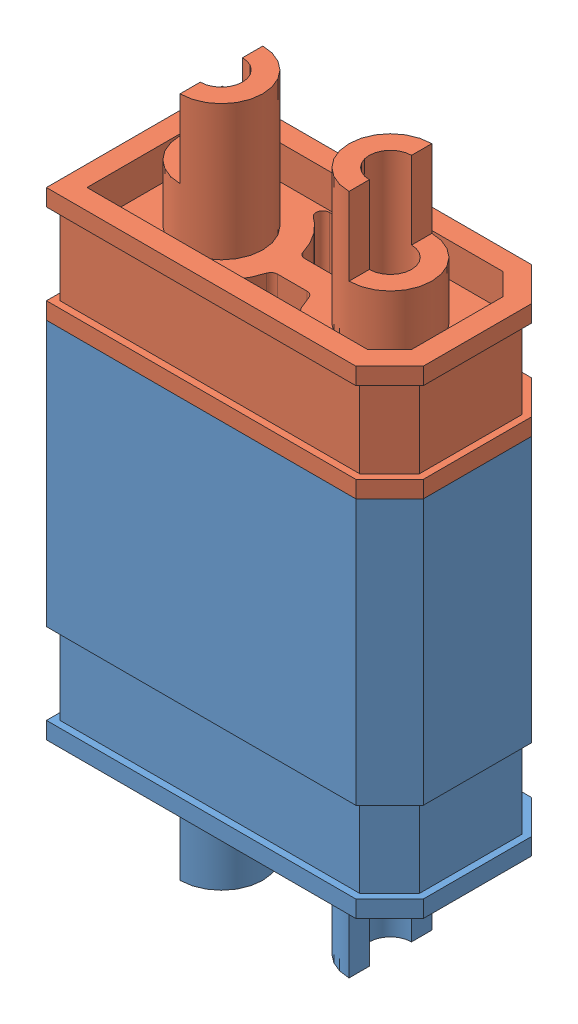
SolidWorks assembly xt30, configuration Default. Lengths in mm.
Overall size (10.15 20.15 5.2).
2 component instances, 2 part files, 6 mates.
Components (placement in the parent):
- xt30-male-1: xt30-male [Default] at origin size (10.15 13.75 5.2)
- xt30-female-1: xt30-female [Default] at (0 14.15 0) x (1 0 0) z (0 0 -1) size (10.15 12.4 5.2)
Mates (geometry in assembly coordinates):
- Concentric1: concentric: cylinder of xt30-male-1 through (-2.5 13.5784 0) axis (0 -1 0) radius 1; cylinder of xt30-female-1 through (-2.5 25.5545 0) axis (0 -1 0) radius 1
- Concentric4: concentric: cylinder of xt30-male-1 through (2.5 13.5784 0) axis (0 -1 0) radius 1; cylinder of xt30-female-1 through (2.5 25.5545 0) axis (0 -1 0) radius 1
- Coincident2: coincident: plane of xt30-male-1 through (0 10.75 0) normal (0 1 0); plane of xt30-female-1 through (0 10.75 0) normal (0 -1 0)
- Concentric6: concentric: cylinder of xt30-male-1 through (-2.5 -3 0) axis (0 1 0) radius 1.225; cylinder of ? through (-2.5 0 0) axis (0 -1 0) radius 1.4
- Concentric7: concentric: cylinder of xt30-male-1 through (2.5 -3 0) axis (0 1 0) radius 1.225; cylinder of ? through (2.5 0 0) axis (0 -1 0) radius 1.4
- Coincident3: coincident: plane of xt30-male-1 through (0 0 0) normal (0 -1 0); plane of ? through (0 0 0) normal (0 1 0)
